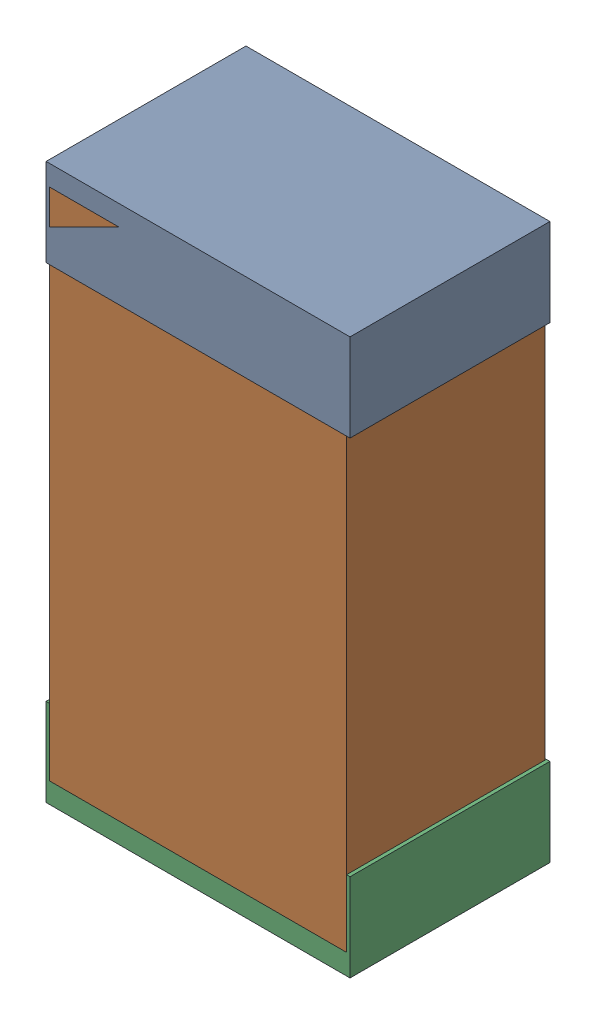
SolidWorks assembly R28Kanaloa_v2.0.0_Motor, configuration Default. Lengths in mm.
Overall size (1.3 2.38 0.85).
6 component instances, 2 part files, 0 mates.
Components (placement in the parent):
- 330415056-1: 330415056 [Default] at (81.788 100.255 -1.9574) size (1.3 0.38 0.85)
  - Extruded_2-1: Extruded_2 [Default] at origin size (1.3 0.38 0.85)
- 334787376-1: 334787376 [Default] at (81.788 99.255 -1.9524) size (1.27 2.2 0.85)
  - Extruded_16-1: Extruded_16 [Default] at origin size (1.27 2.2 0.85)
- 330415056-2: 330415056 [Default] at (81.788 98.255 -1.9574) size (1.3 0.38 0.85)
  - Extruded_2-1: Extruded_2 [Default] at origin size (1.3 0.38 0.85)
